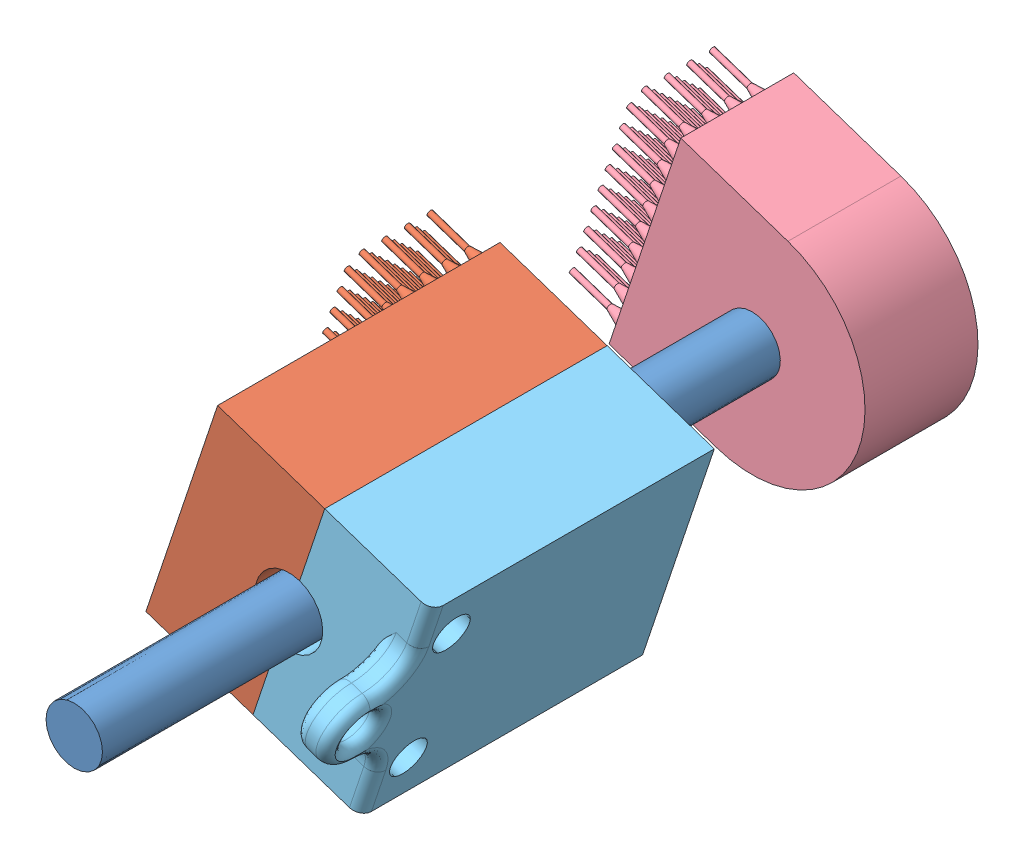
SolidWorks assembly muscle_unit, configuration ﾃﾞﾌｫﾙﾄ. Lengths in mm.
Overall size (30.19 26.94 70).
5 component instances, 5 part files, 9 mates.
Components (placement in the parent):
- axis-1: axis [ﾃﾞﾌｫﾙﾄ] at (0.0076 -0.3556 25) size (5 5 70)
- kenzan_up-1: kenzan_up [ﾃﾞﾌｫﾙﾄ] at (0.0076 -0.3556 51) x (0.948329 -0.31729 0) z (0 0 1) size (15 20 25)
- linear_bush-1: linear_bush [ﾃﾞﾌｫﾙﾄ] at (0.0076 -0.3556 53.25) x (0.529345 -0.848407 0) z (0 0 1) size (10 10 17)
- kenzan_down-1: kenzan_down [ﾃﾞﾌｫﾙﾄ] at (0.0076 -0.3556 35) x (0.948329 -0.31729 0) z (0 0 -1) size (25 20 10)
- kenzan_up_other-1: kenzan_up_other [ﾃﾞﾌｫﾙﾄ] at (0.0076 -0.3556 51) x (-0.948329 0.31729 0) z (0 0 1) size (10.14 20 31)
Mates (geometry in assembly coordinates):
- 同心円1: concentric: cylinder of axis-1 through (0.0076 -0.3556 95) axis (0 0 -1) radius 2.5; cylinder of kenzan_up-1 through (0.0076 -0.3556 76) axis (0 0 -1) radius 3
- 同心円2: concentric: cylinder of axis-1 through (0.0076 -0.3556 95) axis (0 0 -1) radius 2.5; circle of linear_bush-1
- 距離1: distance = 0.25 mm: plane of linear_bush-1 through (0.0076 -0.3556 70.25) normal (0 0 1); plane of kenzan_up-1 through (0.0076 -0.3556 70.5) normal (0 0 -1)
- 同心円4: concentric: cylinder of axis-1 through (0.0076 -0.3556 95) axis (0 0 -1) radius 2.5; cylinder of kenzan_down-1 through (0.0076 -0.3556 25) axis (0 0 1) radius 2.5
- 一致4: coincident: plane of kenzan_up-1 through (-6.3028 12.3006 76) normal (-0.948329 0.31729 0); plane of kenzan_down-1 through (-12.6486 -6.666 25) normal (-0.948329 0.31729 0)
- 一致5: coincident: circle of kenzan_up-1; circle of kenzan_up_other-1
- 同心円5: concentric: cylinder of kenzan_up-1 through (-16.1211 -1.2862 73) axis (0.948329 -0.31729 0) radius 1.6; cylinder of kenzan_up_other-1 through (7.5871 -9.2185 73) axis (-0.948329 0.31729 0) radius 1.6
- 距離制限1: limit distance = 16 mm: plane of kenzan_down-1 through (0.0076 -0.3556 35) normal (0 0 1); plane of kenzan_up-1 through (0.0076 -0.3556 51) normal (0 0 -1)
- 一致9: coincident: plane of axis-1 through (0.0076 -0.3556 25) normal (0 0 -1); plane of kenzan_down-1 through (0.0076 -0.3556 25) normal (0 0 -1)
